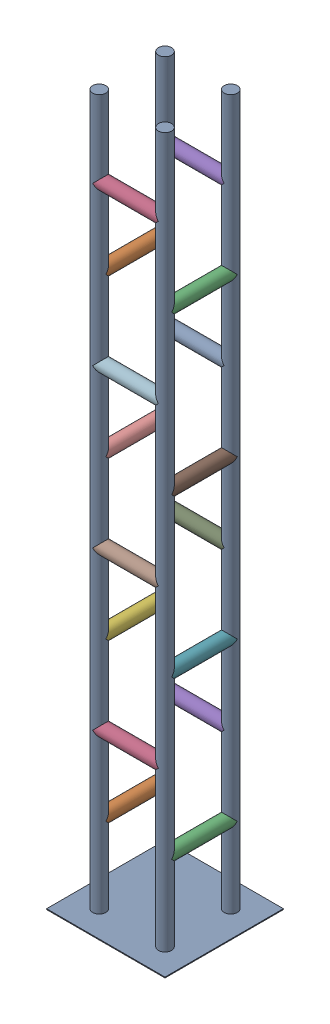
SolidWorks assembly truss, configuration Default. Lengths in mm.
Overall size (457.2 2743.2 457.2).
17 component instances, 2 part files, 0 mates.
Components (placement in the parent):
- truss part 1-1: truss part 1 [Default] at (242.2525 -1375.5385 368.8851) size (457.2 2743.2 457.2)
- truss part 2-1: truss part 2 [Default] at (115.2525 -1067.5635 241.8851) x (-1 0 0) z (0 0 1) size (50.81 50.81 254.01)
- truss part 2-2: truss part 2 [Default] at (369.2525 -1067.5635 495.8851) x (-1 0 0) z (0 0 -1) size (50.81 50.81 254.01)
- truss part 2-3: truss part 2 [Default] at (369.2525 -762.7635 495.8851) x (0 0 -1) z (-1 0 0) size (50.81 50.81 254.01)
- truss part 2-4: truss part 2 [Default] at (369.2525 -762.7635 241.8851) x (0 0 1) z (-1 0 0) size (50.81 50.81 254.01)
- truss part 2-5: truss part 2 [Default] at (115.2525 -457.9635 241.8851) x (-1 0 0) z (0 0 1) size (50.81 50.81 254.01)
- truss part 2-6: truss part 2 [Default] at (369.2525 -457.9635 495.8851) x (-1 0 0) z (0 0 -1) size (50.81 50.81 254.01)
- truss part 2-7: truss part 2 [Default] at (369.2525 -153.1635 495.8851) x (0 0 -1) z (-1 0 0) size (50.81 50.81 254.01)
- truss part 2-8: truss part 2 [Default] at (369.2525 -153.1635 241.8851) x (0 0 1) z (-1 0 0) size (50.81 50.81 254.01)
- truss part 2-9: truss part 2 [Default] at (115.2525 151.6365 241.8851) x (-1 0 0) z (0 0 1) size (50.81 50.81 254.01)
- truss part 2-10: truss part 2 [Default] at (369.2525 151.6365 495.8851) x (-1 0 0) z (0 0 -1) size (50.81 50.81 254.01)
- truss part 2-11: truss part 2 [Default] at (369.2525 456.4365 495.8851) x (0 0 -1) z (-1 0 0) size (50.81 50.81 254.01)
- truss part 2-12: truss part 2 [Default] at (369.2525 456.4365 241.8851) x (0 0 1) z (-1 0 0) size (50.81 50.81 254.01)
- truss part 2-13: truss part 2 [Default] at (115.2525 761.2365 241.8851) x (-1 0 0) z (0 0 1) size (50.81 50.81 254.01)
- truss part 2-14: truss part 2 [Default] at (369.2525 761.2365 495.8851) x (-1 0 0) z (0 0 -1) size (50.81 50.81 254.01)
- truss part 2-15: truss part 2 [Default] at (369.2525 1066.0365 495.8851) x (0 0 -1) z (-1 0 0) size (50.81 50.81 254.01)
- truss part 2-16: truss part 2 [Default] at (369.2525 1066.0365 241.8851) x (0 0 1) z (-1 0 0) size (50.81 50.81 254.01)
